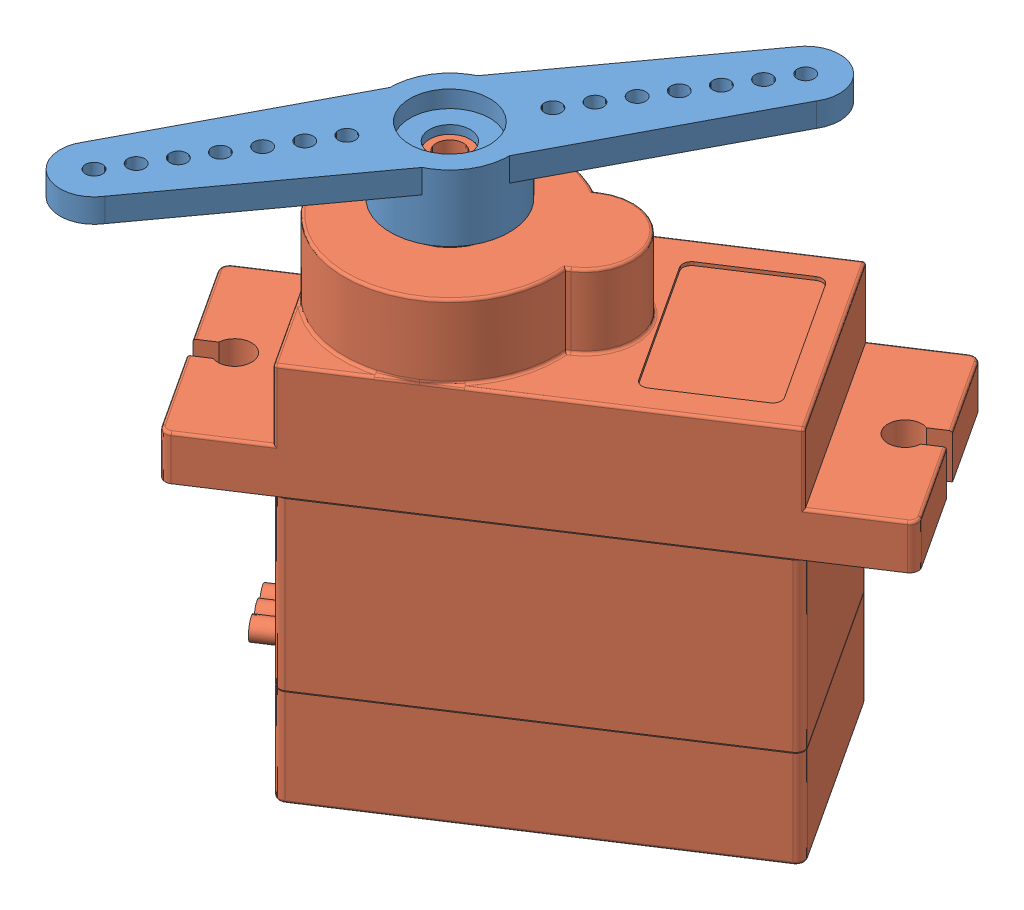
SolidWorks assembly Servo Motor, configuration Default. Lengths in mm.
Overall size (33.88 31.3 33.3).
2 component instances, 2 part files, 2 mates.
Components (placement in the parent):
- microservoArm-1: microservoArm [A2] at (-8.4667 31.3 29.6778) x (0.529063 0 -0.848582) z (-0.848582 0 -0.529063) size (34.4 3.9 7)
- microservoSG90-1: microservoSG90 [Default] at (-4.1971 0 26.8883) x (0.837169 0 -0.546944) z (0.546944 0 0.837169) size (32.3 29.8 12.5)
Mates (geometry in assembly coordinates):
- Concentric1: concentric anti-aligned: cylinder of microservoArm-1 through (-8.4667 27.4 29.6778) axis (0 1 0) radius 2.45; cylinder of microservoSG90-1 through (-8.4667 29.8 29.6778) axis (0 -1 0) radius 2.45
- Coincident1: coincident anti-aligned: plane of microservoArm-1 through (-8.4667 29.8 29.6778) normal (0 -1 0); plane of microservoSG90-1 through (-8.4667 29.8 29.6778) normal (0 1 0)
